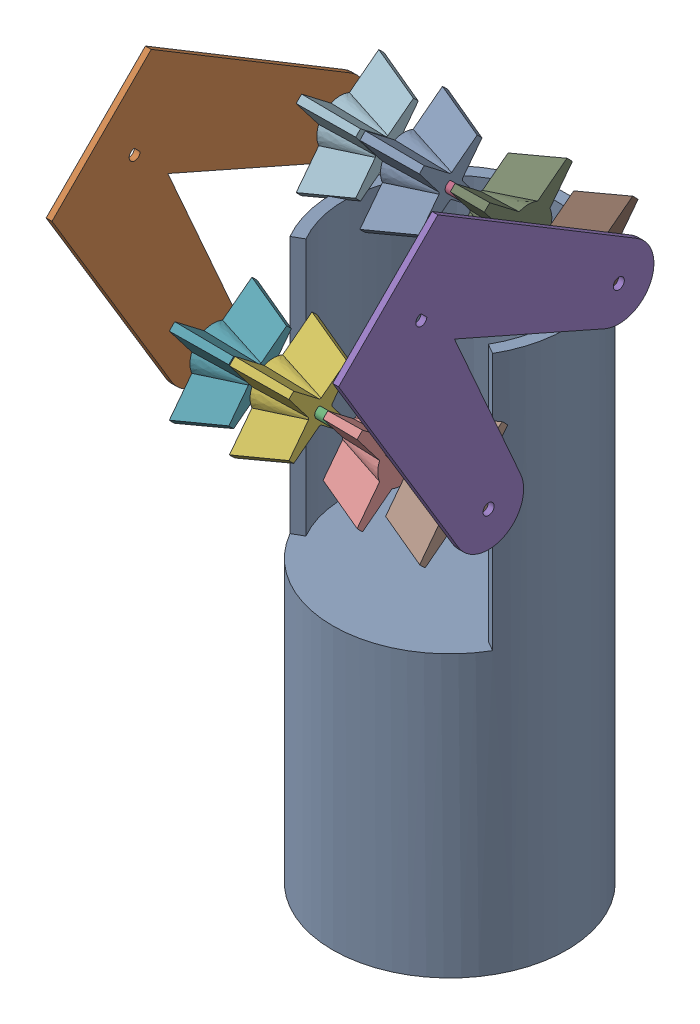
SolidWorks assembly wideIntakePOC, configuration Default. Lengths in mm.
Overall size (158.75 422.28 229.03).
14 component instances, 4 part files, 0 mates.
Components (placement in the parent):
- hollowPillar-1: hollowPillar [Default] at (1.129 -110.1877 171.2722) size (127 292.1 127)
- wideIntake-1: wideIntake [Default] at (-111.4827 287.9719 216.4552) x (0 -0.707107 -0.707107) z (0 -0.707107 0.707107) size (158.77 158.75 163.55)
  - intakeSidePannel-1: intakeSidePannel [Default] at (5.0223 29.747 68.0429) size (146.05 3.17 138.1)
  - 6mmDShaft_4.6in-1: 6mmDShaft_4.6in [Default] at (106.6223 86.5795 118.0429) size (6 116.84 5)
  - 6mmDShaft_4.6in-2: 6mmDShaft_4.6in [Default] at (106.6223 86.5795 18.0429) size (6 116.84 5)
  - intakeSidePannel-2: intakeSidePannel [Default] at (5.0223 185.322 68.0429) size (146.05 3.17 138.1)
  - fourPointIntakeWheel-1: fourPointIntakeWheel [Default] at (106.6223 70.1497 118.0429) size (63.55 25.4 63.55)
  - fourPointIntakeWheel-2: fourPointIntakeWheel [Default] at (106.6223 37.5249 118.0429) size (63.55 25.4 63.55)
  - fourPointIntakeWheel-3: fourPointIntakeWheel [Default] at (106.6223 173.4029 118.0429) x (-1 0 0) z (0 0 1) size (63.55 25.4 63.55)
  - fourPointIntakeWheel-4: fourPointIntakeWheel [Default] at (106.6223 137.8286 18.0429) x (1 0 0) z (0 0 -1) size (63.55 25.4 63.55)
  - fourPointIntakeWheel-5: fourPointIntakeWheel [Default] at (106.6223 139.4633 118.0429) x (1 0 0) z (0 0 -1) size (63.55 25.4 63.55)
  - fourPointIntakeWheel-6: fourPointIntakeWheel [Default] at (106.6223 173.4797 18.0429) x (-1 0 0) z (0 0 1) size (63.55 25.4 63.55)
  - fourPointIntakeWheel-7: fourPointIntakeWheel [Default] at (106.6223 35.676 18.0429) size (63.55 25.4 63.55)
  - fourPointIntakeWheel-8: fourPointIntakeWheel [Default] at (106.6223 70.254 18.0429) size (63.55 25.4 63.55)
